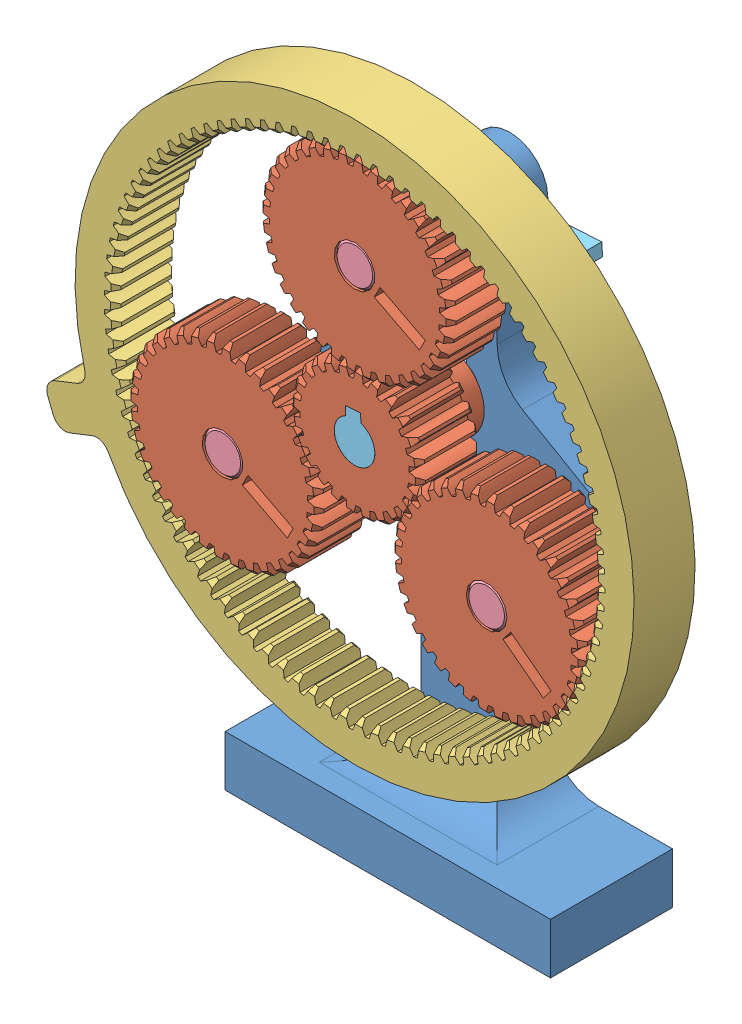
SolidWorks assembly Main Assembly, configuration Default. Lengths in mm.
Overall size (151.47 150.01 45.45).
10 component instances, 5 part files, 25 mates.
Components (placement in the parent):
- Bracket-1: Bracket [Default] at origin size (66.96 116.12 24)
- Gears-1: Gears [Sun Gear] at (0 0 18.542) x (0 0 1) z (-0.997983 -0.063486 0) size (18 25.84 25.84)
- Gears-2: Gears [Planet Gear] at (25.9808 -15 18.5425) x (0 0 1) z (0.607471 0.794342 0) size (18 37.9 37.9)
- Gears-3: Gears [Planet Gear] at (-25.9808 -15 18.5425) x (0 0 1) z (0.459368 0.888246 0) size (18 37.9 37.9)
- Gears-4: Gears [Planet Gear] at (0 30 18.5425) x (0 0 1) z (0.458436 0.888727 0) size (18 37.9 37.9)
- Ring Gear-3: Ring Gear [Default] at (0 0 18.5425) x (0 0 1) z (0.36833 -0.929695 0) size (12 119.35 110)
- Pin-1: Pin [Default] at (0 30 0) x (0.966916 -0.255093 0) z (0 0 1) size (8 8 30.48)
- Pin-2: Pin [Default] at (-25.9808 -15 0) x (0.115736 -0.99328 0) z (0 0 1) size (8 8 30.48)
- Pin-3: Pin [Default] at (25.9808 -15 0.0625) x (0.884406 -0.466718 0) z (0 0 1) size (8 8 30.48)
- Crank-1: Crank [Default] at (0 0 -4.458) x (0.997983 0.063486 0) z (0 0 1) size (8 16.72 45.45)
Mates (geometry in assembly coordinates):
- Concentric1: concentric anti-aligned: cylinder of Bracket-1 through (0 0 0) axis (0 0 1) radius 4; cylinder of Gears-1 through (0 0 36.5441) axis (0 0 -1) radius 4
- Concentric2: concentric anti-aligned: cylinder of Bracket-1 through (25.9808 -15 0) axis (0 0 1) radius 4; cylinder of Gears-2 through (25.9808 -15 36.545) axis (0 0 -1) radius 4
- Concentric3: concentric anti-aligned: cylinder of Bracket-1 through (-25.9808 -15 0) axis (0 0 1) radius 4; cylinder of Gears-3 through (-25.9808 -15 36.545) axis (0 0 -1) radius 4
- Concentric4: concentric anti-aligned: cylinder of Bracket-1 through (0 30 0) axis (0 0 1) radius 4; cylinder of Gears-4 through (0 30 36.545) axis (0 0 -1) radius 4
- Concentric5: concentric anti-aligned: circle of Gears-1; circle of Ring Gear-1
- Distance1: distance = 2.54 mm anti-aligned: plane of Bracket-1 through (0 0 10) normal (0 0 1); plane of Gears-1 through (0 0 12.54) normal (0 0 -1)
- Distance2: distance = 2.54 mm anti-aligned: plane of Bracket-1 through (0 0 10) normal (0 0 1); plane of Gears-2 through (25.9808 -15 12.54) normal (0 0 -1)
- Distance3: distance = 2.54 mm anti-aligned: plane of Bracket-1 through (0 0 10) normal (0 0 1); plane of Gears-3 through (-25.9808 -15 12.54) normal (0 0 -1)
- Distance4: distance = 2.54 mm anti-aligned: plane of Bracket-1 through (0 0 10) normal (0 0 1); plane of Gears-4 through (0 30 12.54) normal (0 0 -1)
- Coincident6: coincident aligned: plane of Gears-4 through (0 30 30.5425) normal (0 0 1); plane of Ring Gear-3 through (-17.3115 43.6957 30.5425) normal (0 0 1)
- GearMate1: gear = 914.4 : 609.6 mm: cylinder of Gears-1 through (0 0 36.5441) axis (0 0 -1) radius 4; cylinder of Gears-4 through (0 30 36.545) axis (0 0 -1) radius 4
- GearMate2: gear = 914.4 : 609.6 mm: cylinder of Gears-1 through (0 0 36.5441) axis (0 0 -1) radius 4; cylinder of Gears-3 through (-25.9808 -15 36.545) axis (0 0 -1) radius 4
- GearMate3: gear = 914.4 : 609.6 mm: cylinder of Gears-1 through (0 0 36.5441) axis (0 0 -1) radius 4; cylinder of Gears-2 through (25.9808 -15 36.545) axis (0 0 -1) radius 4
- GearMate4: gear = 2438.4 : 914.4 mm: cylinder of Gears-4 through (0 30 36.545) axis (0 0 -1) radius 4; cylinder of Ring Gear-3 through (0 0 8.5425) axis (0 0 -1) radius 55
- GearMate5: gear = 2438.4 : 914.4 mm: cylinder of Gears-3 through (-25.9808 -15 36.545) axis (0 0 -1) radius 4; cylinder of Ring Gear-3 through (0 0 8.5425) axis (0 0 -1) radius 55
- GearMate6: gear = 2438.4 : 914.4 mm: cylinder of Gears-2 through (25.9808 -15 36.545) axis (0 0 -1) radius 4; cylinder of Ring Gear-3 through (0 0 8.5425) axis (0 0 -1) radius 55
- Coincident7: coincident aligned: plane of Pin-1 through (0 30 0) normal (0 0 -1); plane of Bracket-1 through (0 0 0) normal (0 0 -1)
- Coincident81: coincident anti-aligned: point of Gears-2; plane of Pin-3 through (25.9808 -15 30.5425) normal (0 0 1)
- Coincident9: coincident aligned: plane of Bracket-1 through (0 0 0) normal (0 0 -1); plane of Pin-2 through (-25.9808 -15 0) normal (0 0 -1)
- Concentric7: concentric aligned: cylinder of Gears-2 through (25.9808 -15 36.545) axis (0 0 -1) radius 4; cylinder of Pin-3 through (25.9808 -15 30.5425) axis (0 0 -1) radius 4
- Concentric6: concentric aligned: cylinder of Gears-4 through (0 30 36.545) axis (0 0 -1) radius 4; cylinder of Pin-1 through (0 30 30.48) axis (0 0 -1) radius 4
- Concentric8: concentric aligned: cylinder of Gears-3 through (-25.9808 -15 36.545) axis (0 0 -1) radius 4; cylinder of Pin-2 through (-25.9808 -15 30.48) axis (0 0 -1) radius 4
- Concentric9: concentric anti-aligned: cylinder of Bracket-1 through (0 0 0) axis (0 0 1) radius 4; cylinder of Crank-1 through (0 0 30.542) axis (0 0 -1) radius 4
- Coincident82: coincident aligned: plane of Gears-1 through (0 0 30.542) normal (0 0 1); plane of Crank-1 through (0 0 30.542) normal (0 0 1)
- Coincident85: coincident anti-aligned: plane of Gears-1 through (1.1541 5.4843 36.5441) normal (-0.997983 -0.063486 0); plane of Crank-1 through (1.497 0.0952 12.542) normal (0.997983 0.063486 0)
